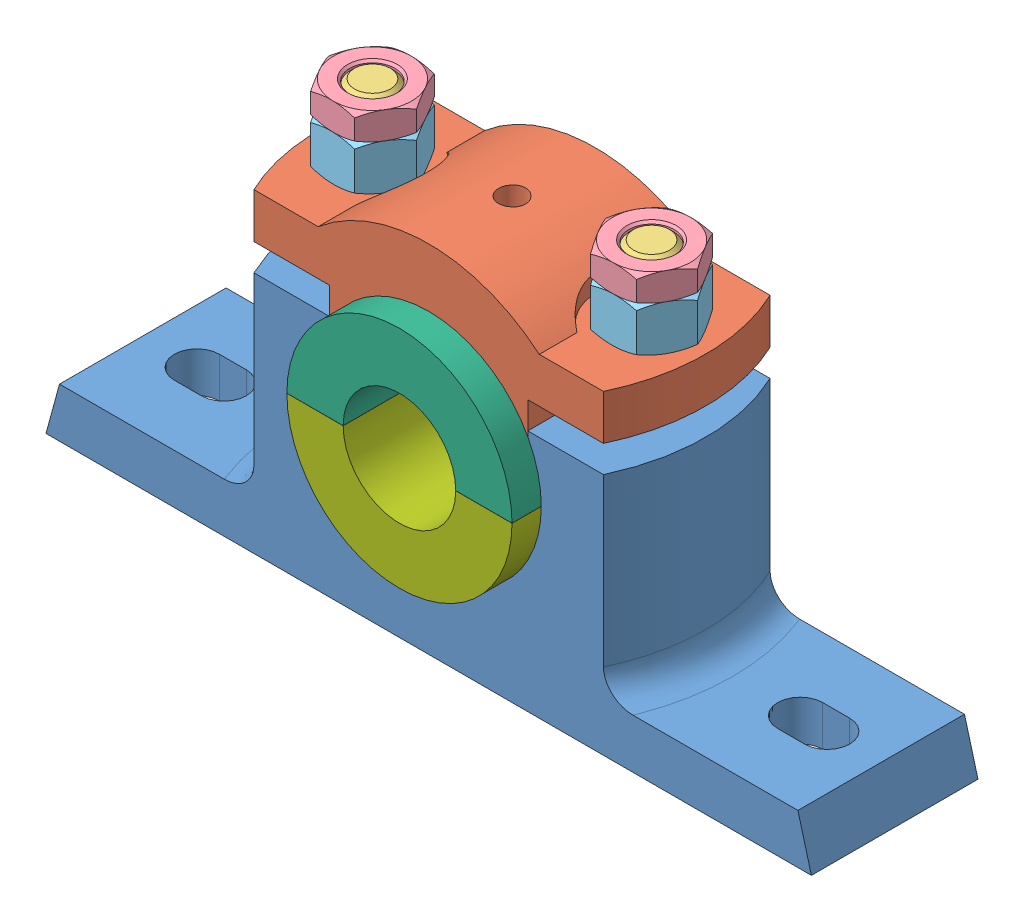
SolidWorks assembly Plummer Block, configuration Default. Lengths in mm.
Overall size (170 86 50).
10 component instances, 7 part files, 17 mates.
Components (placement in the parent):
- Casting-1: Casting [Default] at (97.0286 57.0477 115.9451) size (170 54 37)
- Cap-1: Cap [Default] at (97.0286 98.0477 115.9451) size (86 32 37)
- Bolt-1: Bolt [Default] at (66.0286 59.0477 115.9451) x (0.999999 0 0.001486) z (0 1 0) size (19.5 19.5 84)
- Lock Nut-1: Lock Nut [Default] at (66.0286 140.0477 115.9451) x (0.999459 0 0.032881) z (-0.032881 0 0.999459) size (20 6 18.98)
- Nut-1: Nut [Default] at (66.0286 132.0477 115.9451) x (0.999938 0 0.01112) z (0.01112 0 -0.999938) size (20 10 18.98)
- Lock Nut-2: Lock Nut [Default] at (128.0286 140.0477 115.9451) x (-0.999459 0 0.032881) z (0.032881 0 0.999459) size (20 6 18.98)
- Nut-2: Nut [Default] at (128.0286 132.0477 115.9451) x (-0.999938 0 0.01112) z (-0.01112 0 -0.999938) size (20 10 18.98)
- Bolt-2: Bolt [Default] at (128.0286 59.0477 115.9451) x (0.999999 0 -0.001486) z (0 1 0) size (19.5 19.5 84)
- Upper Block-1: Upper Block [Default] at (97.0286 98.0477 115.9451) x (0 1 0) z (1 0 0) size (25 50 50)
- Lower Block-1: Lower Block [Default] at (97.0286 98.0183 115.9451) x (0 1 0) z (1 0 0) size (25 50 50)
Mates (geometry in assembly coordinates):
- Coincident1: coincident aligned: plane of Casting-1 through (97.0286 57.0477 134.4451) normal (0 0 1); plane of Cap-1 through (97.0286 98.0477 134.4451) normal (0 0 1)
- Coincident2: coincident anti-aligned: plane of Casting-1 through (119.0286 111.0477 88.9451) normal (-1 0 0); plane of Cap-1 through (119.0286 104.0477 134.4451) normal (1 0 0)
- Distance1: distance = 6 mm anti-aligned: plane of Casting-1 through (119.0286 98.0477 88.9451) normal (0 1 0); plane of Cap-1 through (115.0563 104.0477 134.4451) normal (0 -1 0)
- Concentric1: concentric anti-aligned: cylinder of Casting-1 through (66.0286 57.0477 115.9451) axis (0 1 0) radius 5; cylinder of Bolt-1 through (66.0286 143.0477 115.9451) axis (0 -1 0) radius 5
- Coincident4: coincident anti-aligned: plane of Casting-1 through (97.0286 65.0477 115.9451) normal (0 -1 0); plane of Bolt-1 through (66.0286 65.0477 115.9451) normal (0 1 0)
- Concentric2: concentric anti-aligned: circle of Bolt-1; circle of Nut-1
- Coincident5: coincident anti-aligned: plane of Cap-1 through (54.0286 127.0477 134.4451) normal (0 1 0); plane of Nut-1 through (66.0286 127.0477 115.9451) normal (0 -1 0)
- Concentric3: concentric aligned: circle of Bolt-1; circle of Lock Nut-1
- Coincident6: coincident anti-aligned: plane of Lock Nut-1 through (66.0286 137.0477 115.9451) normal (0 -1 0); plane of Nut-1 through (66.0286 137.0477 115.9451) normal (0 1 0)
- Coincident7: coincident aligned: plane of Lock Nut-1 through (60.8389 143.0477 124.4938) normal (-0.022002 0 0.999758); plane of Nut-1 through (70.8371 127.0477 124.7138) normal (-0.022002 0 0.999758)
- Concentric8: concentric aligned: cylinder of Cap-1 through (97.0286 98.0477 134.4451) axis (0 0 -1) radius 19; cylinder of Upper Block-1 through (97.0286 98.0477 126.9451) axis (0 0 -1) radius 17.5
- Width1: width aligned: plane of Upper Block-1 through (97.0286 98.0477 140.9451) normal (0 0 1); plane of Upper Block-1 through (97.0286 98.0477 90.9451) normal (0 0 -1); plane of Cap-1 through (97.0286 98.0477 134.4451) normal (0 0 1); plane of Cap-1 through (97.0286 98.0477 97.4451) normal (0 0 -1)
- Concentric9: concentric aligned: cylinder of Cap-1 through (97.0286 123.0477 115.9451) axis (0 1 0) radius 3; cylinder of Upper Block-1 through (97.0286 98.0477 115.9451) axis (0 1 0) radius 3
- Concentric10: concentric anti-aligned: cylinder of Casting-1 through (97.0286 98.0183 88.9451) axis (0 0 1) radius 19; cylinder of Lower Block-1 through (97.0286 98.0183 126.9451) axis (0 0 -1) radius 17.5
- Width2: width aligned: plane of Lower Block-1 through (97.0286 98.0183 140.9451) normal (0 0 1); plane of Lower Block-1 through (97.0286 98.0183 90.9451) normal (0 0 -1); plane of Casting-1 through (97.0286 57.0477 134.4451) normal (0 0 1); plane of Casting-1 through (97.0286 57.0477 97.4451) normal (0 0 -1)
- Parallel2: parallel anti-aligned: plane of Upper Block-1 through (72.0286 98.0477 -62.3081) normal (0 -1 0); plane of Lower Block-1 through (72.0286 98.0183 -62.3081) normal (0 1 0)
- Coincident8: coincident aligned: plane of Upper Block-1 through (97.0286 98.0477 140.9451) normal (0 0 1); plane of Lower Block-1 through (97.0286 98.0183 140.9451) normal (0 0 1)
